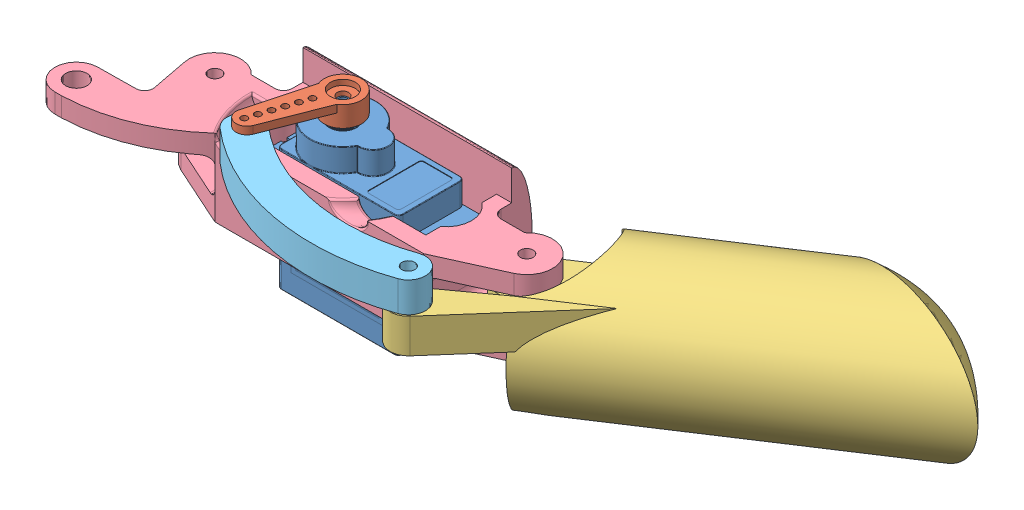
SolidWorks assembly Index-Annulaire, configuration Default. Lengths in mm.
Overall size (137.83 31.75 77.18).
6 component instances, 5 part files, 13 mates.
Components (placement in the parent):
- SG90 - Micro Servo Assembly-1: SG90 - Micro Servo Assembly [Default] at (4.8971 14.1291 22.7262) size (32.1 31.75 22.59) (flexible)
  - SG90 - Micro Servo 9g - Tower Pro.1-2: SG90 - Micro Servo 9g - Tower Pro.1 [Peça] at origin size (32.1 29.95 12.4)
  - SG90 - Micro Servo 9g - Tower Pro.2-2: SG90 - Micro Servo 9g - Tower Pro.2 [Peça] at (-5.15 21.1 0) x (0.31223 0 -0.950007) z (0.950007 0 0.31223) size (19.5 3.8 6.9)
- phalange2_Index-Annulaire-1: phalange2_Index-Annulaire [Défaut] at (28.5635 19.0073 30.9138) x (0 -1 0) z (-0.836367 0 0.548171) size (29.57 28.17 79.44)
- SG90 - Servo Socket-1: SG90 - Servo Socket [Default] at (-14.194 26.1193 32.4496) x (1 0 0) z (0 1 0) size (78.25 28.27 25.4)
- Bras de levier-1: Bras de levier [Default] at (20.1 28.2411 7.5858) x (0 1 0) z (0.32987 0 0.944026) size (5.59 39.35 25.4)
Mates (geometry in assembly coordinates):
- Parallel1: parallel anti-aligned: plane of SG90 - Micro Servo Assembly-1/SG90 - Micro Servo 9g - Tower Pro.1-2 through (-10.3029 21.7791 28.8262) normal (0 0 1); plane of SG90 - Servo Socket-1 through (-6.7169 11.8953 29.2746) normal (0 0 -1)
- Coincident3: coincident anti-aligned: plane of SG90 - Micro Servo Assembly-1/SG90 - Micro Servo 9g - Tower Pro.1-2 through (-10.3029 19.2791 27.9762) normal (0 -1 0); plane of SG90 - Servo Socket-1 through (-14.194 19.2791 32.4496) normal (0 1 0)
- Parallel2: parallel anti-aligned: plane of SG90 - Micro Servo Assembly-1/SG90 - Micro Servo 9g - Tower Pro.1-2 through (-6.3529 74.1738 17.4762) normal (-1 0 0); plane of SG90 - Servo Socket-1 through (-11.7969 19.2791 16.1778) normal (1 0 0)
- Concentric3: concentric aligned: circle of SG90 - Micro Servo Assembly-1/SG90 - Micro Servo 9g - Tower Pro.1-2; circle of SG90 - Servo Socket_V2-1
- Concentric4: concentric aligned: circle of phalange2-1; circle of SG90 - Servo Socket-1
- Distance2: distance = 0.381 mm anti-aligned: plane of phalange2-1 through (84.3477 22.1823 -16.2812) normal (0 1 0); plane of SG90 - Servo Socket-1 through (33.939 22.5633 22.9246) normal (0 -1 0)
- Coaxiale1: concentric anti-aligned: cylinder of SG90 - Micro Servo Assembly-1/SG90 - Micro Servo 9g - Tower Pro.2-2 through (-4.7646 35.2291 36.4538) axis (0 1 0) radius 0.6; cylinder of Bras de levier-1 through (-4.7646 33.8291 36.4538) axis (0 -1 0) radius 0.9922
- Coaxiale2: concentric anti-aligned: cylinder of phalange2-1 through (32.6681 4.2105 43.5532) axis (0 1 0) radius 1.7859; cylinder of Bras de levier-1 through (32.6681 33.8291 43.5532) axis (0 -1 0) radius 1.1906
- Coïncidente1: coincident anti-aligned: plane of SG90 - Micro Servo Assembly-1/SG90 - Micro Servo 9g - Tower Pro.2-2 through (-0.2529 33.8291 22.7262) normal (0 -1 0); plane of Bras de levier-1 through (26.3841 33.8291 25.5695) normal (0 1 0)
- Coaxiale3: concentric anti-aligned: circle of SG90 - Micro Servo Assembly-1/SG90 - Micro Servo 9g - Tower Pro.2-2; circle of 92453A856_BRASS ROUND HEAD SLOTTED MACHINE SCREW-1
- Coïncidente2: coincident anti-aligned: plane of Bras de levier-1 through (26.3841 28.2411 25.5695) normal (0 -1 0); plane of 92453A856_BRASS ROUND HEAD SLOTTED MACHINE SCREW-1 through (-4.7646 28.2411 36.4538) normal (0 1 0)
- Coïncidente3: coincident anti-aligned: plane of SG90 - Micro Servo Assembly-1/SG90 - Micro Servo 9g - Tower Pro.2-2 through (-0.2529 35.2291 22.7262) normal (0 1 0); plane of 90001A403_TYPE 18-8 STAINLESS STEEL HEX NUT-1 through (-3.6207 35.2291 36.5169) normal (0 -1 0)
- Coaxiale4: concentric anti-aligned: circle of SG90 - Micro Servo Assembly-1/SG90 - Micro Servo 9g - Tower Pro.2-2; circle of 90001A403_TYPE 18-8 STAINLESS STEEL HEX NUT-1
